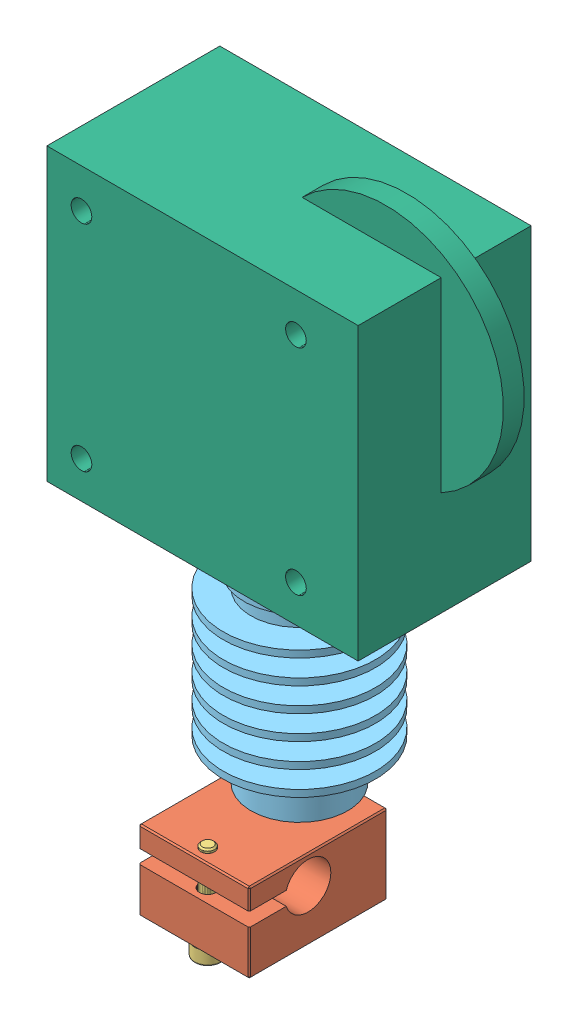
SolidWorks assembly E3D Titan Extruder, configuration Default. Lengths in mm.
Overall size (54 96.06 28.75).
8 component instances, 6 part files, 3 mates.
Components (placement in the parent):
- p_E3D.V6-1.75mm_0.3Nozzle_wPushIn_Bowden_-1: p_E3D.V6-1.75mm_0.3Nozzle_wPushIn_Bowden_ [Défaut] at (16.7586 -33.2186 70.9521) x (0 0 1) z (-1 0 0) size (27.2 60.7 23.91)
  - Nozzle 0.3mm^p_E3D.V6-1.75mm_0.3Nozzle_wPushIn_Bowden_-1: Nozzle 0.3mm^p_E3D.V6-1.75mm_0.3Nozzle_wPushIn_Bowden_ [Défaut] at origin size (8.08 13.04 7) (virtual)
  - Heater_Block^p_E3D.V6-1.75mm_0.3Nozzle_wPushIn_Bowden_-1: Heater_Block^p_E3D.V6-1.75mm_0.3Nozzle_wPushIn_Bowden_ [Défaut] at (0 5 0) x (1 0 0) z (0 1 0) size (20 16 11.5) (virtual)
  - socket head cap screw_din-3: socket head cap screw_din [DIN 912 M2 x 12 --- 12C] at (13.25 3 0) x (0 1 0) z (0 0 1) size (14 3.8 3.8)
  - socket head cap screw_din-4: socket head cap screw_din [DIN 912 M2.5 x 4 --- 4C] at (-1.25 11.5 10.5) x (0 0 -1) z (1 0 0) size (6.5 4.5 4.5)
  - Heatbreak^p_E3D.V6-1.75mm_0.3Nozzle_wPushIn_Bowden_-1: Heatbreak^p_E3D.V6-1.75mm_0.3Nozzle_wPushIn_Bowden_ [Défaut] at (0 12.5 0) x (0.99999 0 0.004447) z (-0.004447 0 0.99999) size (7.01 23.53 7.2) (virtual)
  - Heatsink^p_E3D.V6-1.75mm_0.3Nozzle_wPushIn_Bowden_-1: Heatsink^p_E3D.V6-1.75mm_0.3Nozzle_wPushIn_Bowden_ [Défaut] at (0 60.7 0) x (-0.995869 0 -0.090804) z (-0.090804 0 0.995869) size (22 42.7 22) (virtual)
- Extruder Block-1: Extruder Block [Default] at (14.2586 36.7814 57.4521) size (54 47.06 25)
Mates (geometry in assembly coordinates):
- Distance3: distance = 1 mm aligned: plane of p_E3D.V6-1.75mm_0.3Nozzle_wPushIn_Bowden_-1/Heatsink^p_E3D.V6-1.75mm_0.3Nozzle_wPushIn_Bowden_-1 through (16.7586 14.7814 70.9521) normal (0 -1 0); plane of Extruder Block-1 through (-8.2414 15.7814 82.4521) normal (0 -1 0)
- Distance1: distance = 12 mm aligned: plane of p_E3D.V6-1.75mm_0.3Nozzle_wPushIn_Bowden_-1/Heater_Block^p_E3D.V6-1.75mm_0.3Nozzle_wPushIn_Bowden_-1 through (24.7586 -16.7186 66.2021) normal (1 0 0); plane of Extruder Block-1 through (36.7586 15.7814 82.4521) normal (1 0 0)
- Distance2: distance = 8.75 mm aligned: plane of p_E3D.V6-1.75mm_0.3Nozzle_wPushIn_Bowden_-1/Heater_Block^p_E3D.V6-1.75mm_0.3Nozzle_wPushIn_Bowden_-1 through (24.7586 -16.7186 66.2021) normal (0 0 -1); plane of Extruder Block-1 through (14.2586 36.7814 57.4521) normal (0 0 -1)
